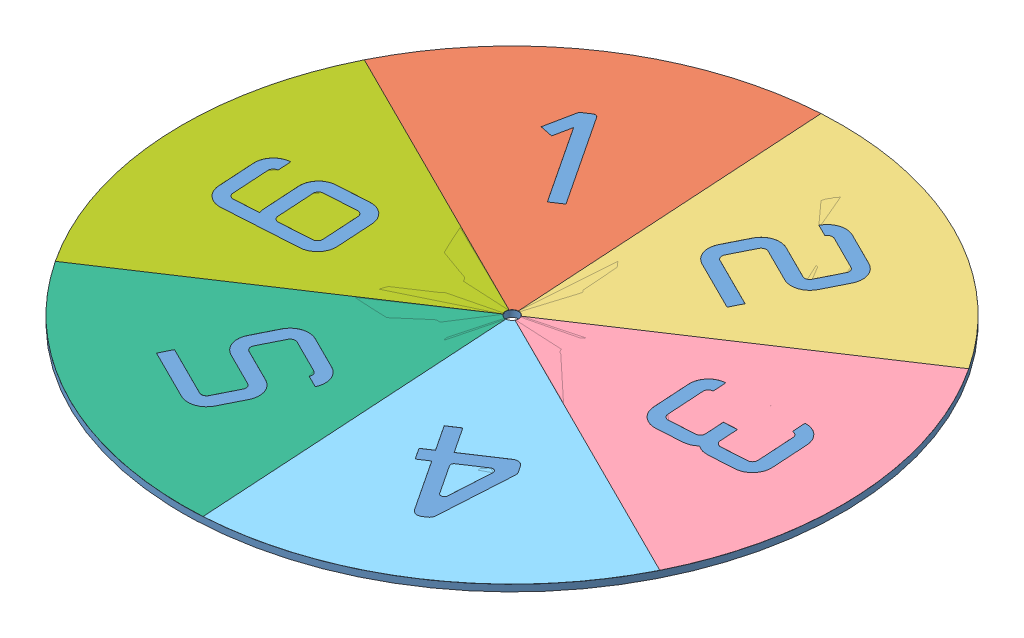
SolidWorks assembly disk, configuration Default. Lengths in mm.
Overall size (102.85 1.1 111.81).
7 component instances, 7 part files, 17 mates.
Components (placement in the parent):
- Part3-1: Part3 [Default] at origin size (100 1 100)
- tri1-2: tri1 [Default] at (0.3823 13.7792 -16.6628) x (0.834076 0 -0.551649) z (0.551649 0 0.834076) size (50 0.16 49.21)
- tri2-2: tri2 [Default] at (14.0245 11.5369 -6.6392) x (0.89478 0 0.446506) z (-0.446506 0 0.89478) size (50 0.16 49.21)
- tri3-2: tri3 [Default] at (14.7189 11.5369 12.0447) x (0.060704 0 0.998156) z (-0.998156 0 0.060704) size (50 0.16 49.21)
- tri4-2: tri4 [Default] at (-1.3418 9.3843 12.9166) x (-0.834076 0 0.551649) z (-0.551649 0 -0.834076) size (50 0.16 49.21)
- tri5-3: tri5 [Default] at (-12.2253 13.0617 7.5147) x (-0.89478 0 -0.446506) z (0.446506 0 -0.89478) size (50 0.16 49.21)
- tri6-3: tri6 [Default] at (-10.6194 8.8462 -8.4142) x (-0.060704 0 -0.998156) z (0.998156 0 -0.060704) size (50 0.16 49.21)
Mates (geometry in assembly coordinates):
- Distance1: distance = 0.02 mm anti-aligned: plane of Part3-1 through (0 1 0) normal (0 1 0); plane of tri2-2 through (0 1.02 0) normal (0 -1 0)
- Concentric1: concentric aligned: circle of Part3-1; circle of tri2-2
- Distance2: distance = 0.02 mm anti-aligned: plane of Part3-1 through (0 1 0) normal (0 1 0); plane of tri1-2 through (0 1.02 0) normal (0 -1 0)
- Concentric2: concentric aligned: circle of Part3-1; circle of tri1-2
- Coincident6: coincident anti-aligned: plane of tri1-2 through (-0.0607 1.03 -0.9982) normal (0.998156 0 -0.060704); plane of tri2-2 through (-0.0607 1.03 -0.9982) normal (-0.998156 0 0.060704)
- Distance3: distance = 0.02 mm anti-aligned: plane of Part3-1 through (0 1 0) normal (0 1 0); plane of tri3-2 through (0 1.02 0) normal (0 -1 0)
- Concentric3: concentric aligned: circle of Part3-1; circle of tri3-2
- Coincident9: coincident anti-aligned: plane of tri2-2 through (0.8341 1.03 -0.5516) normal (0.551649 0 0.834076); plane of tri3-2 through (0.8341 1.03 -0.5516) normal (-0.551649 0 -0.834076)
- Distance4: distance = 0.02 mm anti-aligned: plane of Part3-1 through (0 1 0) normal (0 1 0); plane of tri4-2 through (0 1.02 0) normal (0 -1 0)
- Concentric4: concentric aligned: circle of Part3-1; circle of tri4-2
- Coincident12: coincident anti-aligned: plane of tri3-2 through (0.8948 1.03 0.4465) normal (-0.446506 0 0.89478); plane of tri4-2 through (0.8948 1.03 0.4465) normal (0.446506 0 -0.89478)
- Distance7: distance = 0.02 mm anti-aligned: plane of Part3-1 through (0 1 0) normal (0 1 0); plane of tri5-3 through (0 1.02 0) normal (0 -1 0)
- Concentric6: concentric aligned: circle of Part3-1; circle of tri5-3
- Coincident19: coincident anti-aligned: plane of tri4-2 through (0.0607 1.03 0.9982) normal (-0.998156 0 0.060704); plane of tri5-3 through (0.0607 1.03 0.9982) normal (0.998156 0 -0.060704)
- Distance8: distance = 0.02 mm anti-aligned: plane of Part3-1 through (0 1 0) normal (0 1 0); plane of tri6-3 through (0 1.02 0) normal (0 -1 0)
- Concentric7: concentric aligned: circle of Part3-1; circle of tri6-3
- Coincident22: coincident anti-aligned: plane of tri5-3 through (-0.8341 1.03 0.5516) normal (-0.551649 0 -0.834076); plane of tri6-3 through (-0.8341 1.03 0.5516) normal (0.551649 0 0.834076)
